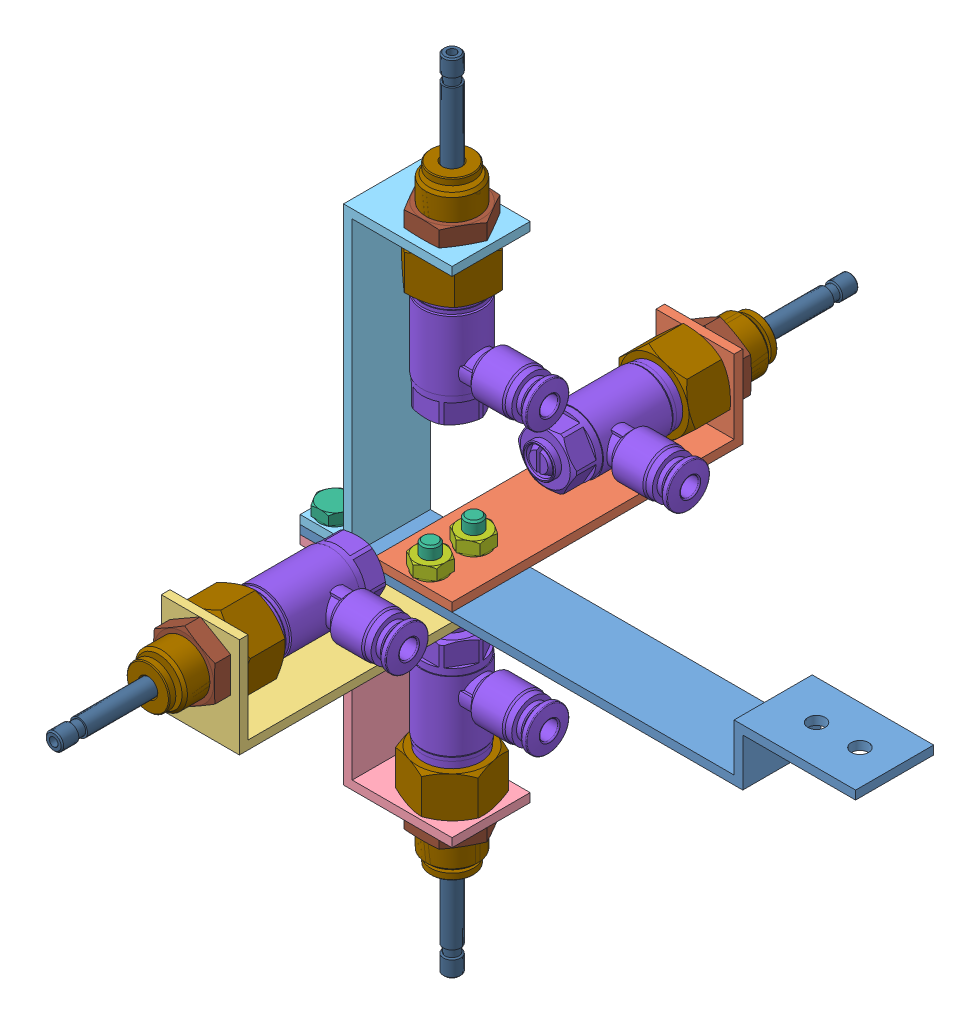
SolidWorks assembly SE_01_1_1000, configuration Default. Lengths in mm.
Overall size (128.04 183.6 183.6).
33 component instances, 11 part files, 47 mates.
Components (placement in the parent):
- SE_01_1_1007-1: SE_01_1_1007 [Default] at origin size (128 13 18)
- SE_01_1_1003-1: SE_01_1_1003 [Default] at (17 0 -49) x (0 0 -1) z (1 0 0) size (67 19 18)
- SE_01_1_1004-1: SE_01_1_1004 [Default] at (35 -4 67) x (0 0 1) z (-1 0 0) size (67 23 18)
- SE_01_1_1005-1: SE_01_1_1005 [Default] at (0 -2 0) x (0 -1 0) z (0 0 1) size (45 35 18)
- SE_01_1_1006-1: SE_01_1_1006 [Default] at (0 0 18) x (0 1 0) z (0 0 -1) size (69 35 18)
- hex screw gradeab_iso-10: hex screw gradeab_iso [ISO 4017 - M4 x 12-N] at (4 4.8 4) x (0 -1 0) z (0 0 1) size (14.8 8.08 7)
- hex screw gradeab_iso-11: hex screw gradeab_iso [ISO 4017 - M4 x 12-N] at (4 4.8 14) x (0 -1 0) z (0 0 1) size (14.8 8.08 7)
- hex nut style 1 gradeab_iso-3: hex nut style 1 gradeab_iso [ISO - 4032 - M4 - W - N] at (4 -7.2 4) x (1 0 0) z (0 -1 0) size (7 8.08 3.2)
- hex nut style 1 gradeab_iso-4: hex nut style 1 gradeab_iso [ISO - 4032 - M4 - W - N] at (4 -7.2 14) x (1 0 0) z (0 -1 0) size (7 8.08 3.2)
- SE_01_1_1001-1: SE_01_1_1001 [Default] at (26 -21.4 9) x (0 0 -1) z (1 0 0) size (24.27 71.9 34.72)
  - SE_01_1_1001_1-1: SE_01_1_1001_1 [Standard] at origin size (13.8 31.75 29.4)
  - SE_01_1_1001_2-1: SE_01_1_1001_2 [Default] at (0 -14.2 0) x (-0.673942 0 -0.738785) z (0 1 0) size (18.48 16 23.5)
  - SE_01_1_1001_3-1: SE_01_1_1001_3 [Default] at (0 -24.4 0) x (0.273272 0 -0.961937) z (0 1 0) size (4 4 35)
- SE_01_1_1001-2: SE_01_1_1001 [Default] at (26 43.4 9) x (0 0 1) z (1 0 0) size (24.27 71.9 34.72)
  - SE_01_1_1001_1-1: SE_01_1_1001_1 [Standard] at origin size (13.8 31.75 29.4)
  - SE_01_1_1001_2-1: SE_01_1_1001_2 [Default] at (0 -14.2 0) x (-0.673942 0 -0.738785) z (0 1 0) size (18.48 16 23.5)
  - SE_01_1_1001_3-1: SE_01_1_1001_3 [Default] at (0 -24.4 0) x (0.273272 0 -0.961937) z (0 1 0) size (4 4 35)
- SE_01_1_1001-3: SE_01_1_1001 [Default] at (26 11 41.4) x (0 -1 0) z (1 0 0) size (24.27 71.9 34.72)
  - SE_01_1_1001_1-1: SE_01_1_1001_1 [Standard] at origin size (13.8 31.75 29.4)
  - SE_01_1_1001_2-1: SE_01_1_1001_2 [Default] at (0 -14.2 0) x (-0.673942 0 -0.738785) z (0 1 0) size (18.48 16 23.5)
  - SE_01_1_1001_3-1: SE_01_1_1001_3 [Default] at (0 -24.4 0) x (0.273272 0 -0.961937) z (0 1 0) size (4 4 35)
- SE_01_1_1001-4: SE_01_1_1001 [Default] at (26 11 -23.4) x (0 1 0) z (1 0 0) size (24.27 71.9 34.72)
  - SE_01_1_1001_1-1: SE_01_1_1001_1 [Standard] at origin size (13.8 31.75 29.4)
  - SE_01_1_1001_2-1: SE_01_1_1001_2 [Default] at (0 -14.2 0) x (-0.673942 0 -0.738785) z (0 1 0) size (18.48 16 23.5)
  - SE_01_1_1001_3-1: SE_01_1_1001_3 [Default] at (0 -24.4 0) x (0.273272 0 -0.961937) z (0 1 0) size (4 4 35)
- SE_01_1_1002-1: SE_01_1_1002 [Default] at (26 11 70.8135) x (0 0 -1) z (1 0 0) size (4 16.17 14)
- SE_01_1_1002-2: SE_01_1_1002 [Default] at (26 73 9) x (0 -1 0) z (0 0 1) size (4 16.17 14)
- SE_01_1_1002-3: SE_01_1_1002 [Default] at (26 -51 9) x (0 1 0) z (0 0 1) size (4 16.17 14)
- SE_01_1_1002-4: SE_01_1_1002 [Default] at (26 11 -53) x (0 0 1) z (-1 0 0) size (4 16.17 14)
- hex screw gradeab_iso-12: hex screw gradeab_iso [ISO 4017 - M4 x 12-N] at (26 -6.8 4) x (0 1 0) z (0 0 1) size (14.8 8.08 7)
- hex screw gradeab_iso-13: hex screw gradeab_iso [ISO 4017 - M4 x 12-N] at (26 -6.8 14) x (0 1 0) z (0 0 1) size (14.8 8.08 7)
- hex nut style 1 gradeab_iso-5: hex nut style 1 gradeab_iso [ISO - 4032 - M4 - W - N] at (26 5.2 4) x (1 0 0) z (0 1 0) size (7 8.08 3.2)
- hex nut style 1 gradeab_iso-6: hex nut style 1 gradeab_iso [ISO - 4032 - M4 - W - N] at (26 5.2 14) x (1 0 0) z (0 1 0) size (7 8.08 3.2)
Mates (geometry in assembly coordinates):
- Coincident1: coincident anti-aligned: plane of SE_01_1_1007-1 through (0 0 18) normal (0 1 0); plane of SE_01_1_1003-1 through (35 0 18) normal (0 -1 0)
- Coincident2: coincident anti-aligned: plane of SE_01_1_1007-1 through (102 -2 18) normal (0 -1 0); plane of SE_01_1_1004-1 through (17 -2 65) normal (0 1 0)
- Concentric1: concentric aligned: cylinder of SE_01_1_1007-1 through (26 -2.001 4) axis (0 1 0) radius 2; cylinder of SE_01_1_1003-1 through (26 -0.001 4) axis (0 1 0) radius 2
- Concentric2: concentric aligned: cylinder of SE_01_1_1007-1 through (26 -2.001 4) axis (0 1 0) radius 2; cylinder of SE_01_1_1004-1 through (26 -4.001 4) axis (0 1 0) radius 2
- Concentric5: concentric aligned: cylinder of SE_01_1_1007-1 through (26 -2.001 14) axis (0 1 0) radius 2; cylinder of SE_01_1_1003-1 through (26 -0.001 14) axis (0 1 0) radius 2
- Concentric6: concentric aligned: cylinder of SE_01_1_1007-1 through (26 -2.001 14) axis (0 1 0) radius 2; cylinder of SE_01_1_1004-1 through (26 -4.001 14) axis (0 1 0) radius 2
- Coincident3: coincident anti-aligned: plane of SE_01_1_1007-1 through (0 0 18) normal (0 1 0); plane of SE_01_1_1006-1 through (0 0 0) normal (0 -1 0)
- Coincident4: coincident anti-aligned: plane of SE_01_1_1007-1 through (102 -2 18) normal (0 -1 0); plane of SE_01_1_1005-1 through (0 -2 18) normal (0 1 0)
- Concentric7: concentric anti-aligned: cylinder of SE_01_1_1007-1 through (4 -2.001 14) axis (0 1 0) radius 2; cylinder of SE_01_1_1006-1 through (4 69.001 14) axis (0 -1 0) radius 2
- Concentric8: concentric anti-aligned: cylinder of SE_01_1_1007-1 through (4 -2.001 4) axis (0 1 0) radius 2; cylinder of SE_01_1_1006-1 through (4 69.001 4) axis (0 -1 0) radius 2
- Concentric9: concentric aligned: cylinder of SE_01_1_1007-1 through (4 -2.001 14) axis (0 1 0) radius 2; cylinder of SE_01_1_1005-1 through (4 -47.001 14) axis (0 1 0) radius 2
- Concentric10: concentric aligned: cylinder of SE_01_1_1007-1 through (4 -2.001 4) axis (0 1 0) radius 2; cylinder of SE_01_1_1005-1 through (4 -47.001 4) axis (0 1 0) radius 2
- Concentric181: concentric anti-aligned: cylinder of SE_01_1_1006-1 through (4 69.001 4) axis (0 -1 0) radius 2; cylinder of hex screw gradeab_iso-10 through (4 4.8 4) axis (0 1 0) radius 3.5
- Coincident121: coincident anti-aligned: plane of SE_01_1_1006-1 through (10 2 0) normal (0 1 0); plane of hex screw gradeab_iso-10 through (8.0415 2 4) normal (0 -1 0)
- Concentric191: concentric anti-aligned: cylinder of SE_01_1_1006-1 through (4 69.001 14) axis (0 -1 0) radius 2; cylinder of hex screw gradeab_iso-11 through (4 4.8 14) axis (0 1 0) radius 3.5
- Coincident131: coincident anti-aligned: plane of SE_01_1_1006-1 through (10 2 0) normal (0 1 0); plane of hex screw gradeab_iso-11 through (8.0415 2 14) normal (0 -1 0)
- Concentric221: concentric anti-aligned: cylinder of SE_01_1_1005-1 through (4 -47.001 4) axis (0 1 0) radius 2; cylinder of hex nut style 1 gradeab_iso-3 through (4 17.8375 4) axis (0 -1 0) radius 2
- Coincident161: coincident anti-aligned: plane of SE_01_1_1005-1 through (10 -4 18) normal (0 -1 0); plane of hex nut style 1 gradeab_iso-3 through (4 -4 8.0415) normal (0 1 0)
- Concentric231: concentric anti-aligned: cylinder of SE_01_1_1005-1 through (4 -47.001 14) axis (0 1 0) radius 2; cylinder of hex nut style 1 gradeab_iso-4 through (4 17.8375 14) axis (0 -1 0) radius 2
- Coincident171: coincident anti-aligned: plane of SE_01_1_1005-1 through (10 -4 18) normal (0 -1 0); plane of hex nut style 1 gradeab_iso-4 through (4 -4 18.0415) normal (0 1 0)
- Concentric24: concentric aligned: cylinder of SE_01_1_1003-1 through (26 11 -49.001) axis (0 0 1) radius 6; cylinder of SE_01_1_1001-4/SE_01_1_1001_2-1 through (26 11 -61.1) axis (0 0 1) radius 6
- Coincident18: coincident anti-aligned: plane of SE_01_1_1003-1 through (35 19 -47) normal (0 0 1); plane of SE_01_1_1001-4/SE_01_1_1001_2-1 through (31.9103 16.3915 -47) normal (0 0 -1)
- Concentric25: concentric aligned: cylinder of SE_01_1_1004-1 through (26 11 67.001) axis (0 0 -1) radius 6; cylinder of SE_01_1_1001-3/SE_01_1_1001_2-1 through (26 11 79.1) axis (0 0 -1) radius 6
- Coincident19: coincident anti-aligned: plane of SE_01_1_1004-1 through (17 19 65) normal (0 0 -1); plane of SE_01_1_1001-3/SE_01_1_1001_2-1 through (31.9103 5.6085 65) normal (0 0 1)
- Concentric26: concentric aligned: cylinder of SE_01_1_1006-1 through (26 69.001 9) axis (0 -1 0) radius 6; cylinder of SE_01_1_1001-2/SE_01_1_1001_2-1 through (26 81.1 9) axis (0 -1 0) radius 6
- Coincident20: coincident anti-aligned: plane of SE_01_1_1006-1 through (12 67 0) normal (0 -1 0); plane of SE_01_1_1001-2/SE_01_1_1001_2-1 through (31.9103 67 14.3915) normal (0 1 0)
- Concentric27: concentric aligned: cylinder of SE_01_1_1005-1 through (26 -47.001 9) axis (0 1 0) radius 6; cylinder of SE_01_1_1001-1/SE_01_1_1001_2-1 through (26 -59.1 9) axis (0 1 0) radius 6
- Coincident21: coincident anti-aligned: plane of SE_01_1_1005-1 through (12 -45 18) normal (0 1 0); plane of SE_01_1_1001-1/SE_01_1_1001_2-1 through (31.9103 -45 3.6085) normal (0 -1 0)
- Parallel1: parallel aligned: plane of SE_01_1_1001-3/SE_01_1_1001_1-1 through (33.5 11 39.3) normal (1 0 0); plane of SE_01_1_1007-1 through (102 9 18) normal (1 0 0)
- Parallel2: parallel aligned: plane of SE_01_1_1001-3/SE_01_1_1001_1-1 through (33.5 11 39.3) normal (1 0 0); plane of SE_01_1_1001-4/SE_01_1_1001_1-1 through (33.5 11 -21.3) normal (1 0 0)
- Parallel3: parallel aligned: plane of SE_01_1_1001-3/SE_01_1_1001_1-1 through (33.5 11 39.3) normal (1 0 0); plane of SE_01_1_1001-2/SE_01_1_1001_1-1 through (33.5 41.3 9) normal (1 0 0)
- Parallel4: parallel aligned: plane of SE_01_1_1001-3/SE_01_1_1001_1-1 through (33.5 11 39.3) normal (1 0 0); plane of SE_01_1_1001-1/SE_01_1_1001_1-1 through (33.5 -19.3 9) normal (1 0 0)
- Concentric28: concentric anti-aligned: cylinder of SE_01_1_1001-4/SE_01_1_1001_2-1 through (26 11 -61.1) axis (0 0 1) radius 6; cylinder of SE_01_1_1002-4 through (26 11 -49) axis (0 0 -1) radius 5.4585
- Concentric29: concentric anti-aligned: cylinder of SE_01_1_1001-1/SE_01_1_1001_2-1 through (26 -59.1 9) axis (0 1 0) radius 6; cylinder of SE_01_1_1002-3 through (26 -47 9) axis (0 -1 0) radius 5.4585
- Concentric30: concentric anti-aligned: cylinder of SE_01_1_1001-3/SE_01_1_1001_2-1 through (26 11 79.1) axis (0 0 -1) radius 6; cylinder of SE_01_1_1002-1 through (26 11 66.8135) axis (0 0 1) radius 5.4585
- Concentric31: concentric anti-aligned: cylinder of SE_01_1_1001-2/SE_01_1_1001_2-1 through (26 81.1 9) axis (0 -1 0) radius 6; cylinder of SE_01_1_1002-2 through (26 69 9) axis (0 1 0) radius 5.4585
- Coincident23: coincident anti-aligned: plane of SE_01_1_1003-1 through (35 0 -49) normal (0 0 -1); plane of SE_01_1_1002-4 through (26 17.9 -49) normal (0 0 1)
- Coincident24: coincident anti-aligned: plane of SE_01_1_1005-1 through (35 -47 18) normal (0 -1 0); plane of SE_01_1_1002-3 through (19.1 -47 9) normal (0 1 0)
- Coincident25: coincident anti-aligned: plane of SE_01_1_1006-1 through (35 69 0) normal (0 1 0); plane of SE_01_1_1002-2 through (32.9 69 9) normal (0 -1 0)
- Concentric321: concentric anti-aligned: cylinder of SE_01_1_1004-1 through (26 -4.001 4) axis (0 1 0) radius 2; cylinder of hex screw gradeab_iso-12 through (26 -6.8 4) axis (0 -1 0) radius 3.5
- Coincident261: coincident anti-aligned: plane of SE_01_1_1004-1 through (17 -4 0) normal (0 -1 0); plane of hex screw gradeab_iso-12 through (21.9585 -4 4) normal (0 1 0)
- Concentric331: concentric anti-aligned: cylinder of SE_01_1_1004-1 through (26 -4.001 14) axis (0 1 0) radius 2; cylinder of hex screw gradeab_iso-13 through (26 -6.8 14) axis (0 -1 0) radius 3.5
- Coincident271: coincident anti-aligned: plane of SE_01_1_1004-1 through (17 -4 0) normal (0 -1 0); plane of hex screw gradeab_iso-13 through (21.9585 -4 14) normal (0 1 0)
- Concentric341: concentric aligned: cylinder of SE_01_1_1003-1 through (26 -0.001 4) axis (0 1 0) radius 2; cylinder of hex nut style 1 gradeab_iso-5 through (26 -19.8375 4) axis (0 1 0) radius 2
- Coincident281: coincident anti-aligned: plane of SE_01_1_1003-1 through (35 2 -47) normal (0 1 0); plane of hex nut style 1 gradeab_iso-5 through (26 2 -0.0415) normal (0 -1 0)
- Concentric351: concentric aligned: cylinder of SE_01_1_1003-1 through (26 -0.001 14) axis (0 1 0) radius 2; cylinder of hex nut style 1 gradeab_iso-6 through (26 -19.8375 14) axis (0 1 0) radius 2
- Coincident291: coincident anti-aligned: plane of SE_01_1_1003-1 through (35 2 -47) normal (0 1 0); plane of hex nut style 1 gradeab_iso-6 through (26 2 9.9585) normal (0 -1 0)
